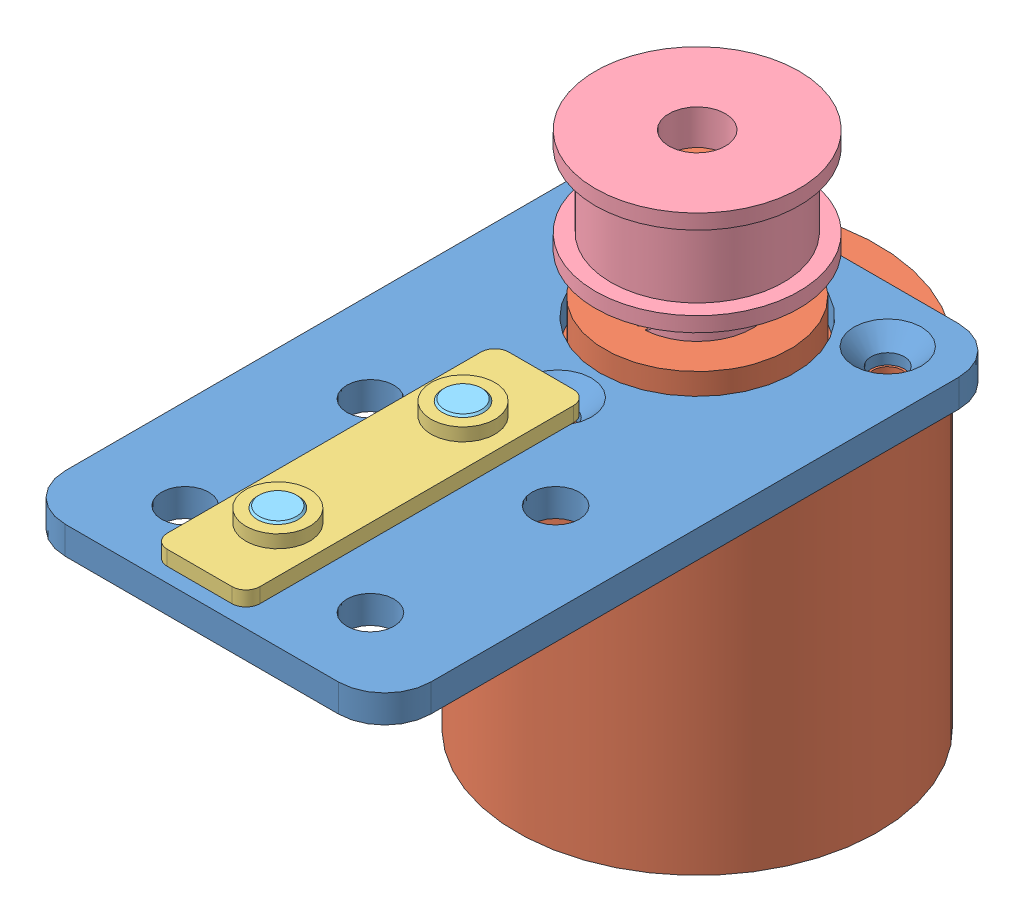
SolidWorks assembly ENCODER_MOUNT, configuration Default. Lengths in mm.
Overall size (51.65 55.93 79.55).
6 component instances, 5 part files, 12 mates.
Components (placement in the parent):
- Encoder_Plate-1: Encoder_Plate [Default] at (31.1909 29.1723 51.0822) size (39.5 3 67)
- ENCODER-1: ENCODER [Default] at (31.1909 29.1723 31.0822) x (0.910312 0 0.413922) z (0 1 0) size (39 39 52.17)
- Double Tee Nut-1: Double Tee Nut [Default] at (36.1909 33.9723 84.8122) x (0 0 -1) z (0 1 0) size (36.88 10 3)
- PULLEY_6MM-1: PULLEY_6MM [Default] at (31.1909 32.1723 31.0822) x (0 1 0) z (0 0 1) size (17.5 22 22)
- LP_SH_SCREW_M5_8mm-1: LP_SH_SCREW_M5_8mm [M5 x 8] at (31.1909 37.1723 56.3722) x (0 1 0) z (0 0 1) size (9.62 9 9)
- LP_SH_SCREW_M5_8mm-2: LP_SH_SCREW_M5_8mm [M5 x 8] at (31.1909 37.1723 76.3722) x (0 1 0) z (0 0 1) size (9.62 9 9)
Mates (geometry in assembly coordinates):
- Coincident1: coincident anti-aligned: plane of Encoder_Plate-1 through (16.4409 29.1723 79.5822) normal (0 -1 0); plane of ENCODER-1 through (31.1909 29.1723 31.0822) normal (0 1 0)
- Concentric4: concentric anti-aligned: cylinder of Encoder_Plate-1 through (31.1909 32.1723 56.3722) axis (0 -1 0) radius 2.55; cylinder of Double Tee Nut-1 through (31.1909 36.9723 56.3722) axis (0 1 0) radius 2.1
- Concentric5: concentric anti-aligned: cylinder of Encoder_Plate-1 through (31.1909 32.1723 76.3722) axis (0 -1 0) radius 2.55; cylinder of Double Tee Nut-1 through (31.1909 36.9723 76.3722) axis (0 1 0) radius 2.1
- Distance2: distance = 1.8 mm anti-aligned: plane of Double Tee Nut-1 through (27.6909 33.9723 49.4322) normal (0 -1 0); plane of Encoder_Plate-1 through (16.4409 32.1723 79.5822) normal (0 1 0)
- Concentric7: concentric anti-aligned: cylinder of ENCODER-1 through (31.1909 34.1253 31.0822) axis (0 -1 0) radius 9.9822; cylinder of PULLEY_6MM-1 through (31.1909 32.1723 31.0822) axis (0 1 0) radius 3.048
- Coincident3: coincident anti-aligned: plane of Encoder_Plate-1 through (16.4409 32.1723 79.5822) normal (0 1 0); plane of PULLEY_6MM-1 through (28.6909 32.1723 31.0822) normal (0 -1 0)
- Concentric8: concentric aligned: cylinder of Encoder_Plate-1 through (18.1485 32.1723 23.5522) axis (0 1 0) radius 1.8; cylinder of ENCODER-1 through (18.1485 24.0923 23.5522) axis (0 1 0) radius 1.58
- Concentric10: concentric anti-aligned: cylinder of Encoder_Plate-1 through (31.1909 29.1723 31.0822) axis (0 1 0) radius 10.5; cylinder of ENCODER-1 through (31.1909 34.1253 31.0822) axis (0 -1 0) radius 9.9822
- Concentric111: concentric anti-aligned: cylinder of Encoder_Plate-1 through (31.1909 32.1723 56.3722) axis (0 -1 0) radius 2.55; cylinder of LP_SH_SCREW_M5_8mm-1 through (31.1909 29.1723 56.3722) axis (0 1 0) radius 2.5
- Coincident41: coincident anti-aligned: plane of Encoder_Plate-1 through (16.4409 29.1723 79.5822) normal (0 -1 0); plane of LP_SH_SCREW_M5_8mm-1 through (27.0294 29.1723 56.3722) normal (0 1 0)
- Concentric121: concentric anti-aligned: cylinder of Encoder_Plate-1 through (31.1909 32.1723 76.3722) axis (0 -1 0) radius 2.55; cylinder of LP_SH_SCREW_M5_8mm-2 through (31.1909 29.1723 76.3722) axis (0 1 0) radius 2.5
- Coincident51: coincident anti-aligned: plane of Encoder_Plate-1 through (16.4409 29.1723 79.5822) normal (0 -1 0); plane of LP_SH_SCREW_M5_8mm-2 through (27.0294 29.1723 76.3722) normal (0 1 0)
